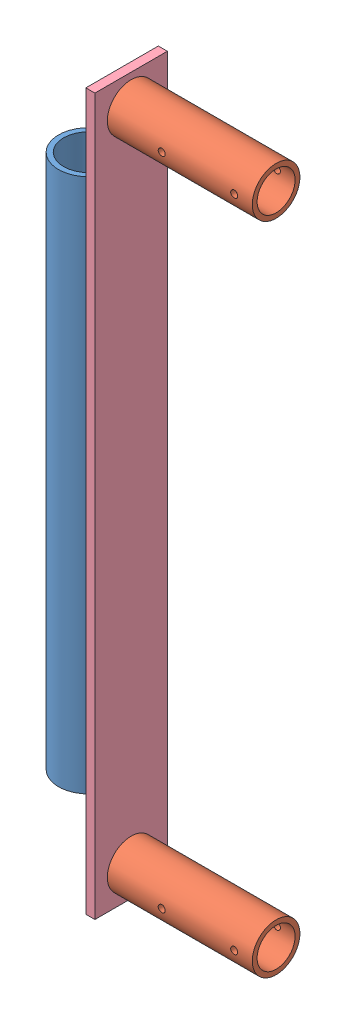
SolidWorks assembly GE-25124, configuration Default. Lengths in mm.
Overall size (152.5 501.65 50.8).
5 component instances, 4 part files, 15 mates.
Components (placement in the parent):
- FE-00018-01-1: FE-00018-01 [Default] at (-29.8133 -187.325 0) size (42.16 374.65 42.16)
- FE-00018-02-1: FE-00018-02 [Default] at (101.6 -229.5684 0) x (0 1 0) z (0 0 1) size (33.4 101.6 33.4)
- FE-00018-02-2: FE-00018-02 [Default] at (101.6 229.5684 0) x (0 -1 0) z (0 0 -1) size (33.4 101.6 33.4)
- FE-00018-04-1: FE-00018-04 [Default] at (-8.7312 -187.325 7.9375) size (2.38 374.65 15.88)
- GE-25126-1: GE-25126 [Default] at (-6.35 0 0) x (0 0 1) z (0 1 0) size (50.8 6.35 501.65)
Mates (geometry in assembly coordinates):
- Coincident14: coincident aligned: plane of Thinner Vert Plate-1 through (0 0 0) normal (1 0 0)
- Coincident15: coincident aligned: plane of Thinner Vert Plate-1 through (-6.35 0 0) normal (0 0 1)
- Coincident16: coincident aligned: plane of Thinner Vert Plate-1 through (-6.35 0 0) normal (0 1 0)
- Symmetric3: symmetric aligned: plane of Thinner Vert Plate-1 through (0 250.825 -25.4) normal (0 0 -1); plane of Thinner Vert Plate-1 through (0 250.825 25.4) normal (0 0 1); plane of FE-00018-01-1 through (-29.8133 -187.325 0) normal (0 0 1)
- Tangent2: tangent anti-aligned: cylinder of FE-00018-01-1 through (-29.8133 187.325 0) axis (0 -1 0) radius 21.082; plane of FE-00018-04-1 through (-8.7312 -187.325 7.9375) normal (-1 0 0)
- Coincident17: coincident aligned: plane of FE-00018-01-1 through (-29.8133 187.325 0) normal (0 1 0); plane of FE-00018-04-1 through (-6.35 187.325 7.9375) normal (0 1 0)
- Symmetric4: symmetric aligned: plane of FE-00018-01-1 through (-29.8133 -187.325 0) normal (0 0 1); plane of FE-00018-04-1 through (-6.35 -187.325 7.9375) normal (0 0 1); plane of FE-00018-04-1 through (-6.35 -187.325 -7.9375) normal (0 0 -1)
- Coincident18: coincident anti-aligned: plane of FE-00018-04-1 through (-6.35 -187.325 7.9375) normal (1 0 0); plane of Thinner Vert Plate-1 through (-6.35 0 0) normal (-1 0 0)
- Width2: width anti-aligned: plane of FE-00018-01-1 through (-29.8133 187.325 0) normal (0 1 0); plane of FE-00018-01-1 through (-29.8133 -187.325 0) normal (0 -1 0); plane of Thinner Vert Plate-1 through (0 -250.825 -25.4) normal (0 -1 0); plane of Thinner Vert Plate-1 through (0 250.825 -25.4) normal (0 1 0)
- Symmetric5: symmetric aligned: plane of ? through (101.6 -231.8764 0) normal (0 0 1); plane of GE-25126-1 through (0 250.825 25.4) normal (0 0 1); plane of GE-25126-1 through (0 250.825 -25.4) normal (0 0 -1)
- Coincident20: coincident anti-aligned: plane of FE-00018-02-1 through (0 -231.8764 0) normal (-1 0 0); plane of Thinner Vert Plate-1 through (0 0 0) normal (1 0 0)
- Symmetric6: symmetric aligned: plane of ? through (101.6 227.2603 0) normal (0 0 -1); plane of GE-25126-1 through (0 250.825 -25.4) normal (0 0 -1); plane of GE-25126-1 through (0 250.825 25.4) normal (0 0 1)
- Coincident21: coincident anti-aligned: plane of FE-00018-02-2 through (0 227.2603 0) normal (-1 0 0); plane of Thinner Vert Plate-1 through (0 0 0) normal (1 0 0)
- Distance1: distance = 459.1368 mm: cylinder of FE-00018-02-2 through (0 229.5684 0) axis (1 0 0) radius 16.7005; cylinder of FE-00018-02-1 through (0 -229.5684 0) axis (1 0 0) radius 16.7005
- Distance2: distance = 229.5684 mm aligned: plane of FE-00018-02-1 through (101.6 -229.5684 0) normal (0 1 0)
